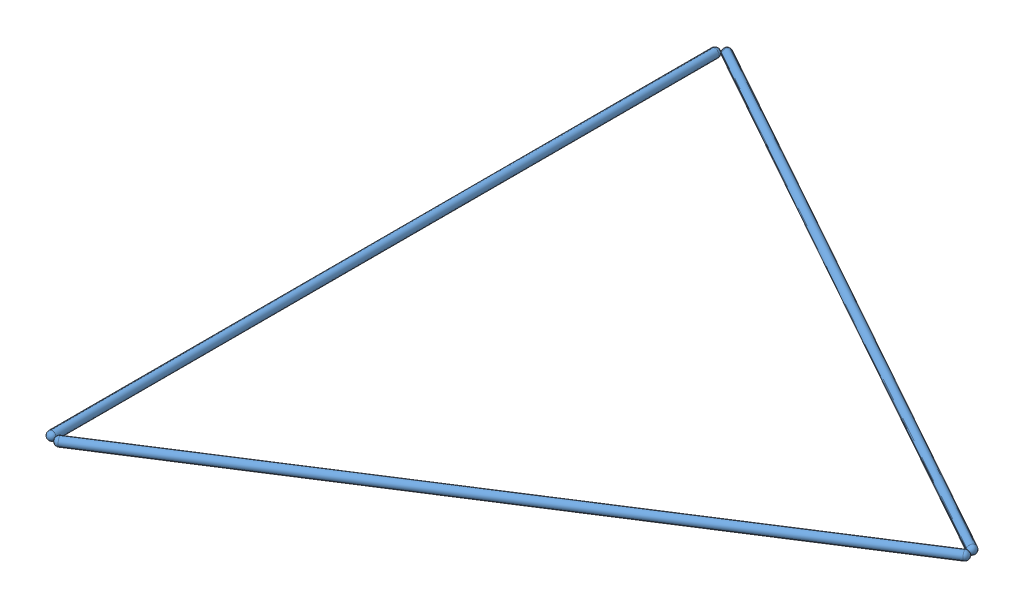
SolidWorks assembly dome_4v_model_1_E_triangle, configuration Default. Lengths in mm.
Overall size (1311.17 70.03 1508.03).
3 component instances, 1 part files, 3 mates.
Components (placement in the parent):
- dome_4v_E_model_1-1: dome_4v_E_model_1 [Default] at (496.3268 1131.1711 962.002) size (19.05 19.05 1485.9)
- dome_4v_E_model_1-2: dome_4v_E_model_1 [Default] at (515.2518 1130.7268 2430.9848) x (0.037678 -0.999287 -0.002331) z (0.865366 0.033795 -0.5) size (19.05 19.05 1485.9)
- dome_4v_E_model_1-3: dome_4v_E_model_1 [Default] at (510.3798 1131.2728 949.1411) x (0.497627 0.000877 -0.867391) z (0.86688 0.033838 0.497368) size (19.05 19.05 1485.9)
Mates (geometry in assembly coordinates):
- Tangent4: tangent: sphere of dome_4v_E_model_1-2; sphere of dome_4v_E_model_1-3
- Tangent5: tangent: sphere of dome_4v_E_model_1-1; sphere of dome_4v_E_model_1-2
- Tangent6: tangent: sphere of dome_4v_E_model_1-1; sphere of dome_4v_E_model_1-3
